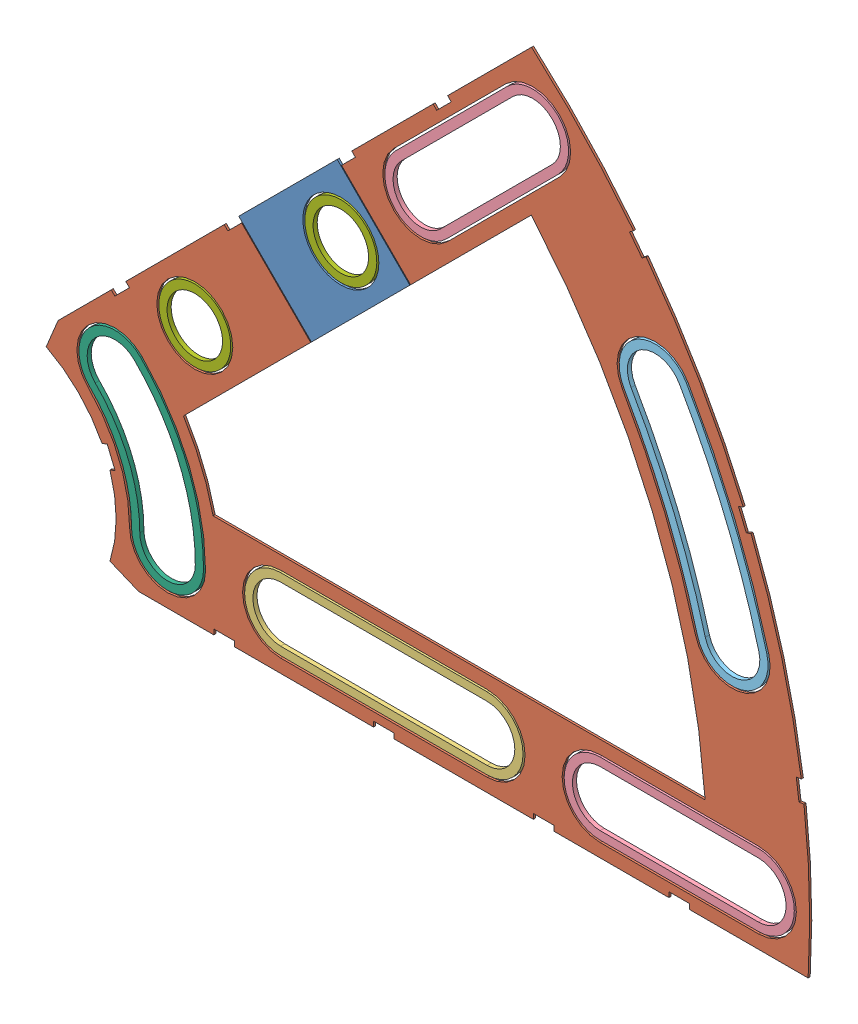
SolidWorks assembly Clover_3_Insul+Pass, configuration Default. Lengths in mm.
Overall size (94.37 82.54 0.51).
9 component instances, 7 part files, 22 mates.
Components (placement in the parent):
- Clover_3_Pass-1: Clover_3_Pass [Default] at (-15.8977 -8.9237 41.0692) size (21.15 21.15 0.25)
- Clover_3_Insul-1: Clover_3_Insul [Default] at (-15.8977 -8.9237 41.0692) size (94.37 82.54 0.25)
- Clover_Long_Washer-1: Clover_Long_Washer [Default] at (33.0608 -8.9237 41.3232) x (1 0 0) z (0 1 0) size (34.42 0.51 8.89)
- Clover_Med_Washer-1: Clover_Med_Washer [Default] at (69.5733 -8.9237 41.3232) x (1 0 0) z (0 1 0) size (28.45 0.51 8.89)
- Clover_Med_Washer-2: Clover_Med_Washer [Default] at (44.5395 51.5134 41.3232) x (0.707107 0.707107 0) z (-0.707107 0.707107 0) size (28.45 0.51 8.89)
- Clover_Outside_Washer-1: Clover_Outside_Washer [Default] at (-15.8977 -8.9237 40.8152) x (0.965926 0.258819 0) z (0.258819 -0.965926 0) size (12.14 0.51 33.54)
- Curve_Inner_Washer-1: Curve_Inner_Washer [Default] at (-15.8977 -8.9237 40.8152) x (1 0 0) z (0 -1 0) size (15.4 0.51 24.61)
- Round_Washer-1: Round_Washer [Default] at (9.6961 16.67 41.3232) x (1 0 0) z (0 1 0) size (8.89 0.51 8.89)
- Round_Washer-2: Round_Washer [Default] at (27.7464 34.7203 41.3232) x (1 0 0) z (0 1 0) size (8.89 0.51 8.89)
Mates (geometry in assembly coordinates):
- Coincident1: coincident: plane of Clover_3_Pass-1 through (-15.8977 -8.9237 41.3232) normal (0 0 1); plane of Clover_3_Insul-1 through (-15.8977 -8.9237 41.3232) normal (0 0 1)
- Coincident2: coincident: plane of Clover_3_Pass-1 through (51.3138 67.268 41.3232) normal (-0.707107 0.707107 0); plane of Clover_3_Insul-1 through (51.3138 67.268 41.3232) normal (-0.707107 0.707107 0)
- Distance1: distance = 2.54 mm: plane of Clover_3_Pass-1 through (27.2974 43.2515 41.0692) normal (0.707107 0.707107 0); plane of Clover_3_Insul-1 through (29.0934 45.0476 41.0692) normal (-0.707107 -0.707107 0)
- Concentric1: concentric: circle of Clover_3_Pass-1; circle of Round_Washer-2
- Coincident3: coincident: plane of Clover_3_Pass-1 through (-15.8977 -8.9237 41.3232) normal (0 0 1); plane of Round_Washer-2 through (27.7464 34.7203 41.3232) normal (0 0 1)
- Concentric2: concentric: circle of Clover_3_Insul-1; circle of Round_Washer-1
- Coincident4: coincident: plane of Clover_3_Insul-1 through (-15.8977 -8.9237 41.3232) normal (0 0 1); plane of Round_Washer-1 through (9.6961 16.67 41.3232) normal (0 0 1)
- Concentric3: concentric: circle of Clover_3_Insul-1; circle of Curve_Inner_Washer-1
- Concentric4: concentric: circle of Clover_3_Insul-1; circle of Curve_Inner_Washer-1
- Coincident5: coincident: plane of Clover_3_Insul-1 through (-15.8977 -8.9237 41.3232) normal (0 0 1); plane of Curve_Inner_Washer-1 through (-4.7852 -8.9237 41.3232) normal (0 0 1)
- Concentric5: concentric: circle of Clover_3_Insul-1; circle of Clover_Long_Washer-1
- Concentric6: concentric: circle of Clover_3_Insul-1; circle of Clover_Long_Washer-1
- Coincident6: coincident: plane of Clover_3_Insul-1 through (-15.8977 -8.9237 41.3232) normal (0 0 1); plane of Clover_Long_Washer-1 through (20.2973 -8.9237 41.3232) normal (0 0 1)
- Concentric7: concentric: circle of Clover_3_Insul-1; circle of Clover_Med_Washer-1
- Concentric8: concentric: circle of Clover_3_Insul-1; circle of Clover_Med_Washer-1
- Coincident7: coincident: plane of Clover_3_Insul-1 through (-15.8977 -8.9237 41.3232) normal (0 0 1); plane of Clover_Med_Washer-1 through (59.7943 -8.9237 41.3232) normal (0 0 1)
- Concentric9: concentric: circle of Clover_3_Insul-1; circle of Clover_Outside_Washer-1
- Concentric10: concentric: circle of Clover_3_Insul-1; circle of Clover_Outside_Washer-1
- Coincident8: coincident: plane of Clover_3_Insul-1 through (-15.8977 -8.9237 41.3232) normal (0 0 1); plane of Clover_Outside_Washer-1 through (30.1046 3.4025 41.3232) normal (0 0 1)
- Concentric11: concentric: circle of Clover_3_Insul-1; circle of Clover_Med_Washer-2
- Concentric12: concentric: circle of Clover_3_Insul-1; circle of Clover_Med_Washer-2
- Coincident9: coincident: plane of Clover_3_Insul-1 through (-15.8977 -8.9237 41.3232) normal (0 0 1); plane of Clover_Med_Washer-2 through (37.6247 44.5986 41.3232) normal (0 0 1)
